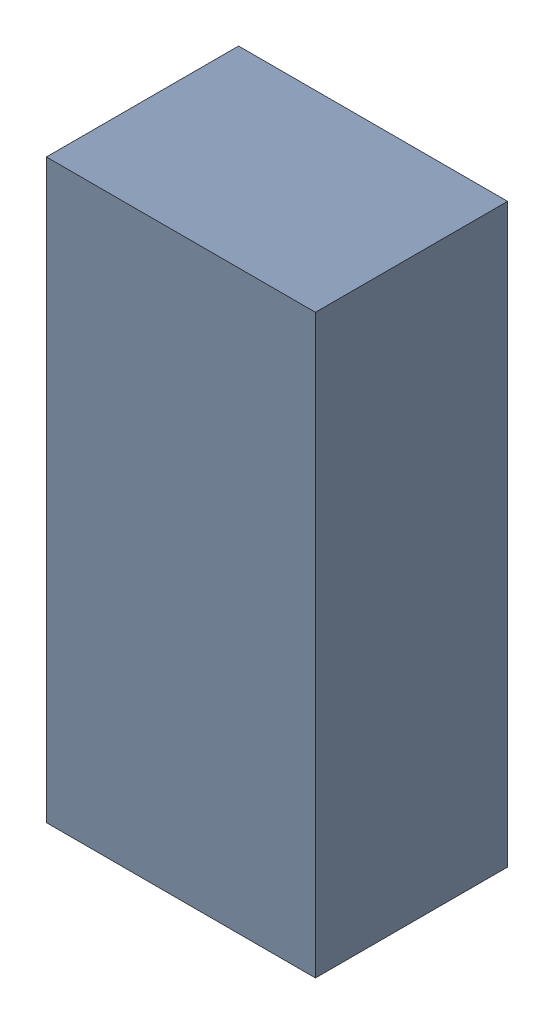
SolidWorks assembly Q2-2, configuration Default. Lengths in mm.
Overall size (1.4 3 1).
2 component instances, 1 part files, 0 mates.
Components (placement in the parent):
- 959206624-2-1: 959206624-2 [Default] at (158.496 90.17 0.1) size (1.4 3 1)
  - Extruded-72-1: Extruded-72 [Default] at origin size (1.4 3 1)
